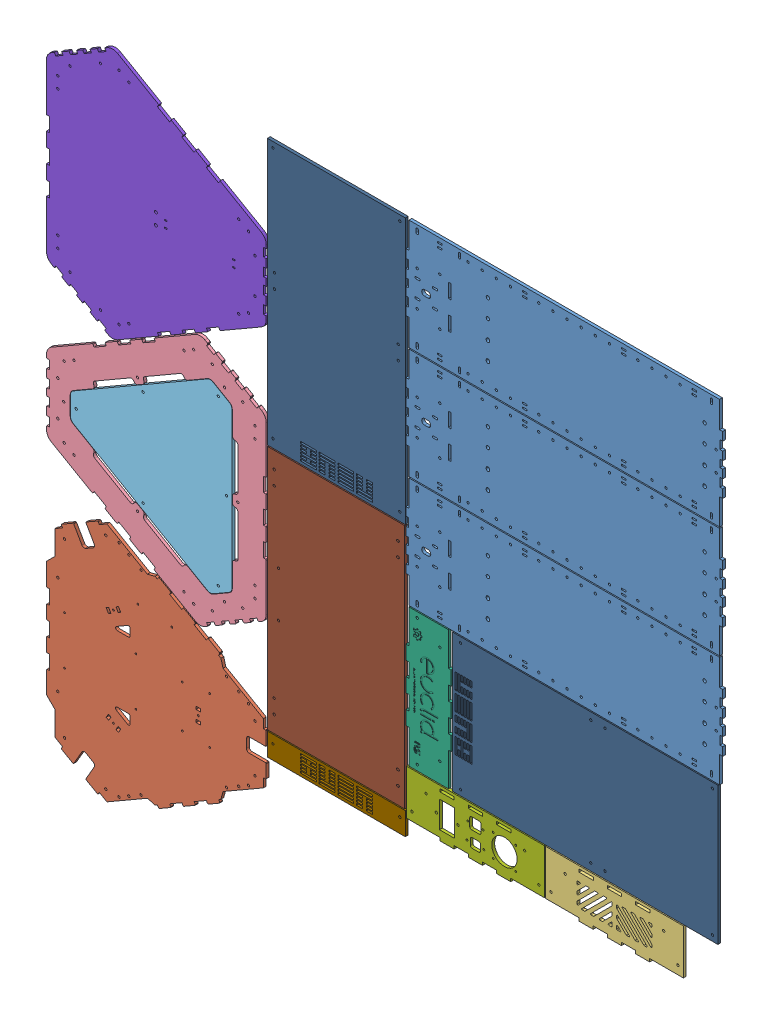
SolidWorks assembly acrylic lasercut layout, configuration Default. Lengths in mm.
Overall size (1200 2400 216.11).
14 component instances, 11 part files, 43 mates.
Components (placement in the parent):
- acrylic-wall-1: acrylic-wall [Default] at (132.9434 705.5226 220) x (0 0 -1) z (0 -1 0) size (5 560 195.39)
- acrylic-wall-2: acrylic-wall [Default] at (132.9434 902.9136 220) x (0 0 -1) z (0 -1 0) size (5 560 195.39)
- acrylic-wall-3: acrylic-wall [Default] at (132.9434 1100.3045 220) x (0 0 -1) z (0 -1 0) size (5 560 195.39)
- acrylic-base-1: acrylic-base [Default] at (-428.8258 253.1843 -15) x (1 0 0) z (0 1 0) size (388.46 5 425.46)
- acrylic-bay-cover-1: acrylic-bay-cover [Default] at (406.5971 370.058 168.4567) x (0.866025 0 -0.5) z (0.5 0 0.866025) size (213.61 85 126.21)
- acrylic-bottom-1: acrylic-bottom [Default] at (-377.2825 614.7693 -90) x (-1 0 0) z (0 -1 0) size (388.46 5 443.29)
- acrylic-electronics-cover-1: acrylic-electronics-cover [Default] at (-377.2825 614.7693 -90) x (-1 0 0) z (0 -1 0) size (285.46 5 326.68)
- acrylic-pscover-1: acrylic-pscover [Default] at (132.9434 483.9426 168.4567) x (0 -0.866025 -0.5) z (0 -0.5 0.866025) size (213.61 80 126.21)
- acrylic-switch-cover-1: acrylic-switch-cover [Default] at (160.828 370.058 168.4567) x (0.866025 0 -0.5) z (0.5 0 0.866025) size (213.61 85 126.21)
- acrylic-top-1: acrylic-top [Default] at (-428.8258 976.3543 -460) x (1 0 0) z (0 -1 0) size (388.46 5 443.29)
- acrylic-nameplate-1: acrylic-nameplate [Default] at (-84.9412 -169 168.4567) x (0.866025 0 -0.5) z (0.5 0 0.866025) size (213.61 40 126.21)
- acrylic-window-bl-1: acrylic-window-bl [Default] at (-84.9412 1188.25 -163.4567) x (0.866025 0 0.5) z (0.5 0 -0.866025) size (213.61 469.5 126.21)
- acrylic-window-bl-2: acrylic-window-bl [Default] at (579.6934 483.9426 168.4567) x (0 0.866025 -0.5) z (0 0.5 0.866025) size (213.61 469.5 126.21)
- acrylic-door-1: acrylic-door [Default] at (-85.4412 307.25 168.4567) x (0.866025 0 -0.5) z (0.5 0 0.866025) size (212.74 433.75 125.71)
Mates (geometry in assembly coordinates):
- Coincident1: coincident anti-aligned: plane of acrylic-wall-3 through (42.9434 1157.9896 0) normal (0 0 -1); plane of assembly through (0 0 0) normal (0 0 1)
- Coincident2: coincident anti-aligned: plane of acrylic-wall-2 through (42.9434 960.5986 0) normal (0 0 -1); plane of assembly through (0 0 0) normal (0 0 1)
- Coincident3: coincident anti-aligned: plane of acrylic-wall-1 through (42.9434 763.2077 0) normal (0 0 -1); plane of assembly through (0 0 0) normal (0 0 1)
- Coincident4: coincident anti-aligned: plane of acrylic-base-1 through (-428.8258 253.1843 0) normal (0 0 -1); plane of assembly through (0 0 0) normal (0 0 1)
- Coincident5: coincident anti-aligned: plane of acrylic-bay-cover-1 through (406.5971 370.058 0) normal (0 0 -1); plane of assembly through (0 0 0) normal (0 0 1)
- Coincident6: coincident anti-aligned: plane of acrylic-pscover-1 through (132.9434 483.9426 0) normal (0 0 -1); plane of assembly through (0 0 0) normal (0 0 1)
- Coincident7: coincident anti-aligned: plane of acrylic-switch-cover-1 through (160.828 370.058 0) normal (0 0 -1); plane of assembly through (0 0 0) normal (0 0 1)
- Coincident8: coincident anti-aligned: plane of acrylic-bottom-1 through (-377.2825 614.7693 0) normal (0 0 -1); plane of assembly through (0 0 0) normal (0 0 1)
- Coincident9: coincident anti-aligned: plane of acrylic-electronics-cover-1 through (-377.2825 614.7693 0) normal (0 0 -1); plane of assembly through (0 0 0) normal (0 0 1)
- Coincident10: coincident anti-aligned: plane of acrylic-top-1 through (-580.2825 829.3937 0) normal (0 0 -1); plane of assembly through (0 0 0) normal (0 0 1)
- Coincident11: coincident anti-aligned: plane of acrylic-nameplate-1 through (-84.9412 -169 0) normal (0 0 -1); plane of assembly through (0 0 0) normal (0 0 1)
- Coincident13: coincident anti-aligned: plane of acrylic-door-1 through (-85.4412 307.25 0) normal (0 0 -1); plane of assembly through (0 0 0) normal (0 0 1)
- Coincident14: coincident anti-aligned: plane of acrylic-window-bl-2 through (579.6934 483.9426 0) normal (0 0 -1); plane of assembly through (0 0 0) normal (0 0 1)
- Distance1: distance = 1 mm anti-aligned: plane of acrylic-window-bl-1 through (36.9434 728.5 0) normal (1 0 0); plane of acrylic-wall-3 through (37.9434 1151.5471 5) normal (-1 0 0)
- Distance2: distance = 2.0566 mm: plane of acrylic-wall-3 through (597.9434 1151.5471 5) normal (1 0 0); line of assembly
- Distance3: distance = 2 mm: plane of acrylic-wall-3 through (42.9434 1198 5) normal (0 1 0); line of assembly
- Distance4: distance = 2 mm anti-aligned: plane of acrylic-top-1 through (-208.8258 976.3543 5) normal (1 0 0); plane of acrylic-window-bl-1 through (-206.8258 728.5 0) normal (-1 0 0)
- Coincident20: coincident aligned: plane of acrylic-wall-2 through (597.9434 954.1561 5) normal (1 0 0); plane of acrylic-wall-3 through (597.9434 1049.062 5) normal (1 0 0)
- Coincident21: coincident aligned: plane of acrylic-wall-1 through (597.9434 756.7652 5) normal (1 0 0); plane of acrylic-wall-2 through (597.9434 851.6711 5) normal (1 0 0)
- Distance5: distance = 2 mm anti-aligned: plane of acrylic-top-1 through (-217.3258 903.9468 5) normal (0.5 -0.866025 0); plane of acrylic-bottom-1 through (-597.2825 682.2693 0) normal (-0.5 0.866025 0)
- Distance6: distance = 0.5 mm anti-aligned: plane of acrylic-bottom-1 through (-377.3842 739.9456 -555) normal (0.5 -0.866025 0); plane of acrylic-electronics-cover-1 through (-377.1342 739.5126 -555) normal (-0.5 0.866025 0)
- Distance7: distance = 0.5 mm anti-aligned: plane of acrylic-bottom-1 through (-485.6374 552.0931 -555) normal (0.5 0.866025 0); plane of acrylic-electronics-cover-1 through (-485.3874 552.5261 -555) normal (-0.5 -0.866025 0)
- Distance8: distance = 2 mm anti-aligned: plane of acrylic-bottom-1 through (-597.2825 547.2693 0) normal (-0.5 -0.866025 0); plane of acrylic-base-1 through (-312.1215 380.3221 34.4365) normal (0.5 0.866025 0)
- Coincident28: coincident aligned: plane of acrylic-bottom-1 through (-597.2825 682.2693 0) normal (-1 0 0); plane of acrylic-base-1 through (-597.2825 136.0498 239.7489) normal (-1 0 0)
- Distance9: distance = 2 mm anti-aligned: plane of acrylic-window-bl-1 through (-206.8258 728.5 0) normal (-1 0 0); plane of acrylic-bottom-1 through (-208.8258 771.5449 0) normal (1 0 0)
- Distance10: distance = 2 mm anti-aligned: plane of acrylic-wall-1 through (42.9434 803.2181 5) normal (0 1 0); plane of acrylic-wall-2 through (42.9434 805.2181 5) normal (0 -1 0)
- Distance12: distance = 2 mm anti-aligned: plane of acrylic-wall-3 through (42.9434 1002.6091 5) normal (0 -1 0); plane of acrylic-wall-2 through (42.9434 1000.6091 5) normal (0 1 0)
- Distance14: distance = 2 mm anti-aligned: plane of acrylic-pscover-1 through (43.1934 605.8272 5) normal (0 1 0); plane of acrylic-wall-1 through (42.9434 607.8272 5) normal (0 -1 0)
- Distance18: distance = 2 mm anti-aligned: plane of acrylic-switch-cover-1 through (38.9434 280.308 5) normal (-1 0 0); plane of acrylic-nameplate-1 through (36.9434 290.75 5) normal (1 0 0)
- Distance19: distance = 2 mm anti-aligned: plane of acrylic-bay-cover-1 through (284.7125 280.308 5) normal (-1 0 0); plane of acrylic-switch-cover-1 through (282.7125 280.308 5) normal (1 0 0)
- Distance21: distance = 2 mm anti-aligned: plane of acrylic-nameplate-1 through (36.9434 290.75 5) normal (0 1 0); plane of acrylic-door-1 through (-85.4412 292.75 455.482) normal (0 -1 0)
- Distance22: distance = 2 mm anti-aligned: plane of acrylic-nameplate-1 through (-206.8258 290.75 5) normal (-1 0 0); plane of acrylic-base-1 through (-208.8258 240.6843 5) normal (1 0 0)
- Distance25: distance = 2 mm anti-aligned: plane of acrylic-door-1 through (-206.8258 726.5 110.3386) normal (-1 0 0); plane of acrylic-bottom-1 through (-208.8258 771.5449 0) normal (1 0 0)
- Distance26: distance = 2 mm anti-aligned: plane of acrylic-door-1 through (35.9434 726.5 110.3386) normal (1 0 0); plane of acrylic-pscover-1 through (37.9434 546.3426 5) normal (-1 0 0)
- Distance27: distance = 2 mm: plane of acrylic-window-bl-1 through (36.9434 1198 -105.5551) normal (0 1 0); line of assembly
- Coincident34: coincident anti-aligned: plane of acrylic-window-bl-1 through (-84.9412 1188.25 0) normal (0 0 -1); plane of assembly through (0 0 0) normal (0 0 1)
- Tangent1: tangent aligned: cylinder of acrylic-top-1 through (-480.369 1181 5) axis (0 0 -1) radius 17; plane of acrylic-window-bl-1 through (36.9434 1198 -105.5551) normal (0 1 0)
- Distance28: distance = 2 mm anti-aligned: plane of acrylic-door-1 through (36.1934 726.5 455.482) normal (0 1 0); plane of acrylic-window-bl-1 through (36.9434 728.5 0) normal (0 -1 0)
- Distance29: distance = 2 mm anti-aligned: plane of acrylic-wall-1 through (42.9434 607.8272 5) normal (0 -1 0); plane of acrylic-window-bl-2 through (119.9434 605.8272 5) normal (0 1 0)
- Distance30: distance = 2 mm anti-aligned: plane of acrylic-window-bl-2 through (119.9434 605.8272 5) normal (-1 0 0); plane of acrylic-pscover-1 through (117.9434 362.058 5) normal (1 0 0)
- Distance31: distance = 2 mm anti-aligned: plane of acrylic-switch-cover-1 through (282.7125 360.058 248.8204) normal (0 1 0); plane of acrylic-window-bl-2 through (119.9434 362.058 5) normal (0 -1 0)
- Coincident40: coincident anti-aligned: plane of acrylic-bay-cover-1 through (406.5971 370.058 0) normal (0 0 -1); plane of assembly through (0 0 0) normal (0 0 1)
- Distance33: distance = 2 mm anti-aligned: plane of acrylic-bay-cover-1 through (284.7125 360.058 -243.8204) normal (0 1 0); plane of acrylic-window-bl-2 through (119.9434 362.058 5) normal (0 -1 0)
